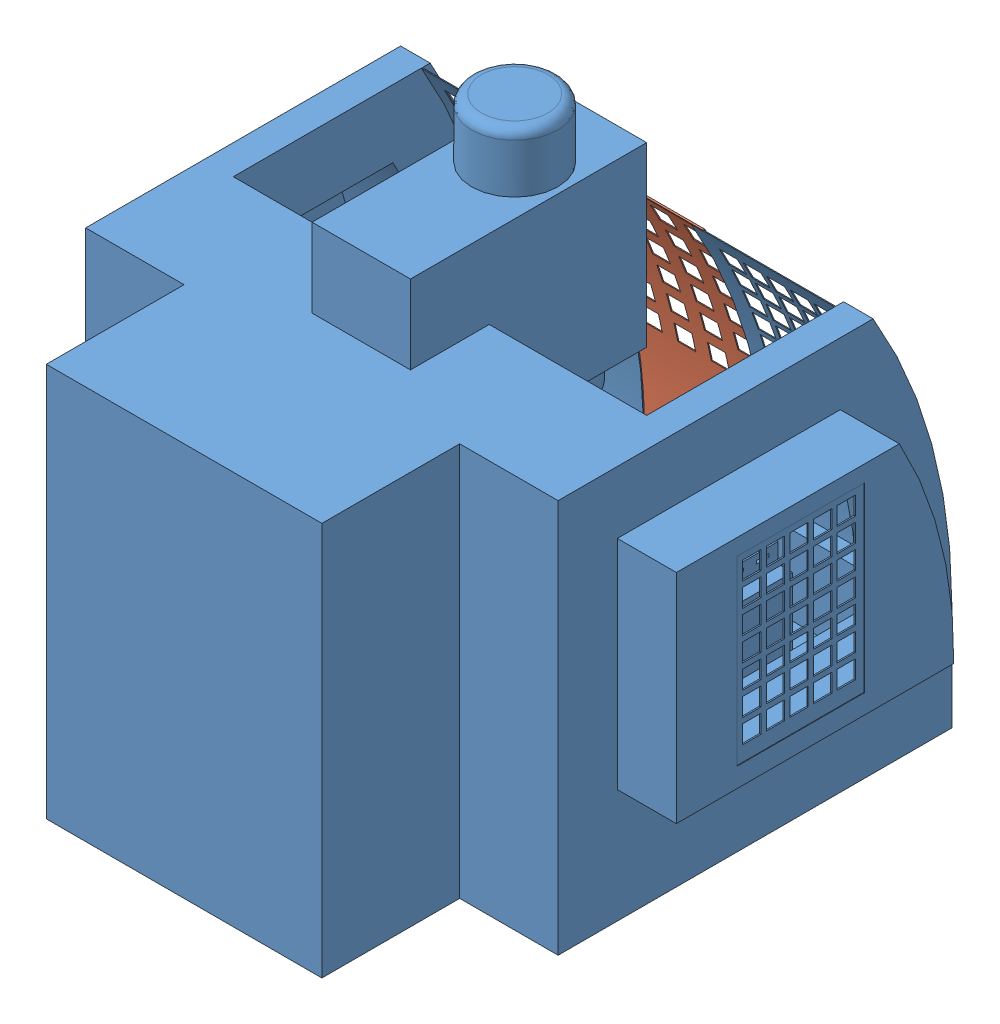
SolidWorks assembly Assieme1, configuration Default. Lengths in mm.
Overall size (3000 2700 2700).
2 component instances, 2 part files, 5 mates.
Components (placement in the parent):
- CNC Milling machine-1: CNC Milling machine [Default] at origin size (3000 2700 2700)
- porta_cnc-1: porta_cnc [Default] at (-320 0 0) x (0 0 -1) z (1 0 0) size (450.86 1402.55 700) (hidden)
Mates (geometry in assembly coordinates):
- Coincidente6: coordinate: point of CNC Milling machine-1
- SulPosto1: in place: plane of CNC Milling machine-1 through (-320 543.29 892.5049) normal (1 0 0); plane of porta_cnc-1 through (-320 0 0) normal (1 0 0); moOrthogonalPlaneRef_w of CNC Milling machine-1 through (-320 543.29 892.5049) normal (1 0 0); plane of porta_cnc-1 through (-320 0 0) normal (0 1 0); plane of CNC Milling machine-1 through (-320 543.29 892.5049) normal (1 0 0); plane of porta_cnc-1 through (-320 0 0) normal (0 0 -1); plane of CNC Milling machine-1 through (-320 543.29 892.5049) normal (1 0 0); unknown of porta_cnc-1
- Coincidente7: coincident aligned: plane of ?; plane of ?
- Coincidente8: coincident aligned: moOrthogonalPlaneRef_w of CNC Milling machine-1 through (-320 0 0) normal (0 1 0); plane of Parte2^Assieme1-1 through (-320 0 0) normal (0 1 0)
- Coincidente9: coincident anti-aligned: moOrthogonalPlaneRef_w of CNC Milling machine-1 through (-320 0 0) normal (0 0 1); plane of Parte2^Assieme1-1 through (-320 0 0) normal (0 0 -1)
